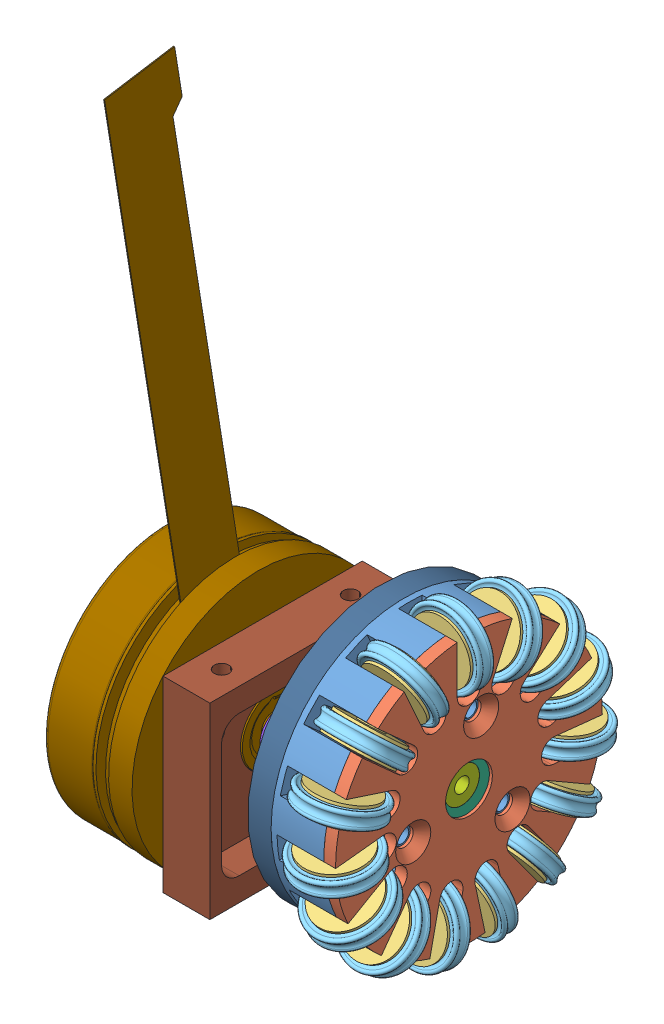
SolidWorks assembly drive_right, configuration Default. Lengths in mm.
Overall size (58.89 137.4 77.93).
70 component instances, 12 part files, 25 mates.
Components (placement in the parent):
- wheel_hub_flat_back-1: wheel_hub_flat_back [Default] at (-31.4027 -2.3485 15.5279) size (9 45.5 45.5)
- wheel_cover-1: wheel_cover [Default] at (-22.4027 -2.3485 15.5279) size (2 45.41 45.5)
- wheel_roller_asm-1: wheel_roller_asm [Default] at (-3.0698 37.2715 -2.2573) x (0.742932 0.669367 0) z (0 0 1) size (12.8 12.8 6)
  - wheel_roller_hub-1: wheel_roller_hub [Default] at (-28.6925 -1.096 17.7852) size (10.4 10.4 3.8)
  - wheel_roller_pin-1: wheel_roller_pin [Default] at (-28.6925 -1.096 14.7852) size (2.5 2.5 6)
  - xring_109-1: xring_109 [Default] at (-28.6925 -1.096 17.7852) size (12.8 12.8 2.6)
- wheel_roller_asm-2: wheel_roller_asm [Default] at (-3.0698 41.0801 15.3952) x (0.742932 0.611497 0.272256) z (0 -0.406737 0.913545) size (12.8 12.8 6)
  - wheel_roller_hub-1: wheel_roller_hub [Default] at (-28.6925 -1.096 17.7852) size (10.4 10.4 3.8)
  - wheel_roller_pin-1: wheel_roller_pin [Default] at (-28.6925 -1.096 14.7852) size (2.5 2.5 6)
  - xring_109-1: xring_109 [Default] at (-28.6925 -1.096 17.7852) size (12.8 12.8 2.6)
- wheel_roller_asm-3: wheel_roller_asm [Default] at (-3.0698 37.3795 33.0707) x (0.742932 0.447894 0.497437) z (0 -0.743145 0.669131) size (12.8 12.8 6)
  - wheel_roller_hub-1: wheel_roller_hub [Default] at (-28.6925 -1.096 17.7852) size (10.4 10.4 3.8)
  - wheel_roller_pin-1: wheel_roller_pin [Default] at (-28.6925 -1.096 14.7852) size (2.5 2.5 6)
  - xring_109-1: xring_109 [Default] at (-28.6925 -1.096 17.7852) size (12.8 12.8 2.6)
- wheel_roller_asm-4: wheel_roller_asm [Default] at (-3.0698 26.8095 47.7129) x (0.742932 0.206846 0.636606) z (0 -0.951057 0.309017) size (12.8 12.8 6)
  - wheel_roller_hub-1: wheel_roller_hub [Default] at (-28.6925 -1.096 17.7852) size (10.4 10.4 3.8)
  - wheel_roller_pin-1: wheel_roller_pin [Default] at (-28.6925 -1.096 14.7852) size (2.5 2.5 6)
  - xring_109-1: xring_109 [Default] at (-28.6925 -1.096 17.7852) size (12.8 12.8 2.6)
- wheel_roller_asm-5: wheel_roller_asm [Default] at (-3.0698 11.1979 56.79) x (0.742932 -0.069968 0.6657) z (0 -0.994522 -0.104528) size (12.8 12.8 6)
  - wheel_roller_hub-1: wheel_roller_hub [Default] at (-28.6925 -1.096 17.7852) size (10.4 10.4 3.8)
  - wheel_roller_pin-1: wheel_roller_pin [Default] at (-28.6925 -1.096 14.7852) size (2.5 2.5 6)
  - xring_109-1: xring_109 [Default] at (-28.6925 -1.096 17.7852) size (12.8 12.8 2.6)
- wheel_roller_asm-6: wheel_roller_asm [Default] at (-3.0698 -6.7561 58.7325) x (0.742932 -0.334684 0.579689) z (0 -0.866025 -0.5) size (12.8 12.8 6)
  - wheel_roller_hub-1: wheel_roller_hub [Default] at (-28.6925 -1.096 17.7852) size (10.4 10.4 3.8)
  - wheel_roller_pin-1: wheel_roller_pin [Default] at (-28.6925 -1.096 14.7852) size (2.5 2.5 6)
  - xring_109-1: xring_109 [Default] at (-28.6925 -1.096 17.7852) size (12.8 12.8 2.6)
- wheel_roller_asm-7: wheel_roller_asm [Default] at (-3.0698 -23.9479 53.2045) x (0.742932 -0.541529 0.393444) z (0 -0.587785 -0.809017) size (12.8 12.8 6)
  - wheel_roller_hub-1: wheel_roller_hub [Default] at (-28.6925 -1.096 17.7852) size (10.4 10.4 3.8)
  - wheel_roller_pin-1: wheel_roller_pin [Default] at (-28.6925 -1.096 14.7852) size (2.5 2.5 6)
  - xring_109-1: xring_109 [Default] at (-28.6925 -1.096 17.7852) size (12.8 12.8 2.6)
- wheel_roller_asm-8: wheel_roller_asm [Default] at (-3.0698 -37.405 41.162) x (0.742932 -0.65474 0.139169) z (0 -0.207912 -0.978148) size (12.8 12.8 6)
  - wheel_roller_hub-1: wheel_roller_hub [Default] at (-28.6925 -1.096 17.7852) size (10.4 10.4 3.8)
  - wheel_roller_pin-1: wheel_roller_pin [Default] at (-28.6925 -1.096 14.7852) size (2.5 2.5 6)
  - xring_109-1: xring_109 [Default] at (-28.6925 -1.096 17.7852) size (12.8 12.8 2.6)
- wheel_roller_asm-9: wheel_roller_asm [Default] at (-3.0698 -44.8005 24.687) x (0.742932 -0.65474 -0.139169) z (0 0.207912 -0.978148) size (12.8 12.8 6)
  - wheel_roller_hub-1: wheel_roller_hub [Default] at (-28.6925 -1.096 17.7852) size (10.4 10.4 3.8)
  - wheel_roller_pin-1: wheel_roller_pin [Default] at (-28.6925 -1.096 14.7852) size (2.5 2.5 6)
  - xring_109-1: xring_109 [Default] at (-28.6925 -1.096 17.7852) size (12.8 12.8 2.6)
- wheel_roller_asm-10: wheel_roller_asm [Default] at (-3.0698 -44.8557 6.6284) x (0.742932 -0.541529 -0.393444) z (0 0.587785 -0.809017) size (12.8 12.8 6)
  - wheel_roller_hub-1: wheel_roller_hub [Default] at (-28.6925 -1.096 17.7852) size (10.4 10.4 3.8)
  - wheel_roller_pin-1: wheel_roller_pin [Default] at (-28.6925 -1.096 14.7852) size (2.5 2.5 6)
  - xring_109-1: xring_109 [Default] at (-28.6925 -1.096 17.7852) size (12.8 12.8 2.6)
- wheel_roller_asm-11: wheel_roller_asm [Default] at (-3.0698 -37.561 -9.8914) x (0.742932 -0.334684 -0.579689) z (0 0.866025 -0.5) size (12.8 12.8 6)
  - wheel_roller_hub-1: wheel_roller_hub [Default] at (-28.6925 -1.096 17.7852) size (10.4 10.4 3.8)
  - wheel_roller_pin-1: wheel_roller_pin [Default] at (-28.6925 -1.096 14.7852) size (2.5 2.5 6)
  - xring_109-1: xring_109 [Default] at (-28.6925 -1.096 17.7852) size (12.8 12.8 2.6)
- wheel_roller_asm-12: wheel_roller_asm [Default] at (-3.0698 -24.1777 -22.016) x (0.742932 -0.069968 -0.6657) z (0 0.994522 -0.104528) size (12.8 12.8 6)
  - wheel_roller_hub-1: wheel_roller_hub [Default] at (-28.6925 -1.096 17.7852) size (10.4 10.4 3.8)
  - wheel_roller_pin-1: wheel_roller_pin [Default] at (-28.6925 -1.096 14.7852) size (2.5 2.5 6)
  - xring_109-1: xring_109 [Default] at (-28.6925 -1.096 17.7852) size (12.8 12.8 2.6)
- wheel_roller_asm-13: wheel_roller_asm [Default] at (-3.0698 -7.02 -27.6489) x (0.742932 0.206846 -0.636606) z (0 0.951057 0.309017) size (12.8 12.8 6)
  - wheel_roller_hub-1: wheel_roller_hub [Default] at (-28.6925 -1.096 17.7852) size (10.4 10.4 3.8)
  - wheel_roller_pin-1: wheel_roller_pin [Default] at (-28.6925 -1.096 14.7852) size (2.5 2.5 6)
  - xring_109-1: xring_109 [Default] at (-28.6925 -1.096 17.7852) size (12.8 12.8 2.6)
- wheel_roller_asm-14: wheel_roller_asm [Default] at (-3.0698 10.9455 -25.8162) x (0.742932 0.447894 -0.497437) z (0 0.743145 0.669131) size (12.8 12.8 6)
  - wheel_roller_hub-1: wheel_roller_hub [Default] at (-28.6925 -1.096 17.7852) size (10.4 10.4 3.8)
  - wheel_roller_pin-1: wheel_roller_pin [Default] at (-28.6925 -1.096 14.7852) size (2.5 2.5 6)
  - xring_109-1: xring_109 [Default] at (-28.6925 -1.096 17.7852) size (12.8 12.8 2.6)
- wheel_roller_asm-15: wheel_roller_asm [Default] at (-3.0698 26.6123 -16.8346) x (0.742932 0.611497 -0.272256) z (0 0.406737 0.913545) size (12.8 12.8 6)
  - wheel_roller_hub-1: wheel_roller_hub [Default] at (-28.6925 -1.096 17.7852) size (10.4 10.4 3.8)
  - wheel_roller_pin-1: wheel_roller_pin [Default] at (-28.6925 -1.096 14.7852) size (2.5 2.5 6)
  - xring_109-1: xring_109 [Default] at (-28.6925 -1.096 17.7852) size (12.8 12.8 2.6)
- MF126ZZ-1: MF126ZZ [Default] at (-21.6027 -2.3485 15.5279) x (-1 0 0) z (0 0.924225 0.381849) size (4 13.6 13.6)
- MF126ZZ-2: MF126ZZ [Default] at (-31.4027 -2.3485 15.5279) size (4 13.6 13.6)
- wheel_rod-1: wheel_rod [Default] at (-21.6027 -2.3485 15.5279) x (-1 0 0) z (0 0.924225 0.381849) size (23 8 8)
- spur_gear-1: spur_gear [Metric - Spur gear 0.5M 20T 20PA 3FW ---S20O8H8L4N] at (-35.4027 2.1015 27.209) x (1 0 0) z (0 0.134505 0.990913) size (8 10.9 10.9)
- EC45fl-200142-1: EC45fl-200142 [Default] at (-44.6027 2.1015 27.209) x (-1 0 0) z (0 -0.158938 0.987289) size (36.9 124.1 43.2)
- internal_gear_70-3: internal_gear_70 [DIN - Internal spur gear 0.5M 70T 20PA 4FW ---S70S45,5OD 1AF] at (-31.4027 -2.3485 15.5279) x (-1 0 0) z (0 -0.207912 -0.978148) size (4 45.5 45.5)
- motor_mount_right-1: motor_mount_right [Default] at (-36.6027 -15.7485 9.5279) x (-1 0 0) z (0 0 -1) size (8 32 34)
- motor_shaft_extension-1: motor_shaft_extension [Default] at (-55.0027 2.1015 27.209) x (-1 0 0) z (0 0.286562 -0.958062) size (18.5 4 4)
Mates (geometry in assembly coordinates):
- Width1: width anti-aligned: plane of wheel_hub_flat_back-1 through (-30.4027 12.1015 17.5279) normal (0 0 -1); plane of wheel_hub_flat_back-1 through (-30.4027 20.4015 13.5279) normal (0 0 1); plane of wheel_roller_asm-1/wheel_roller_hub-1 through (-24.5229 18.2173 17.4279) normal (0 0 1); plane of wheel_roller_asm-1/wheel_roller_hub-1 through (-24.9915 18.7374 13.6279) normal (0 0 -1)
- Distance1: distance = 0 mm aligned: plane of wheel_hub_flat_back-1 through (-22.4027 -2.3485 15.5279) normal (1 0 0); cylinder of wheel_roller_asm-1/wheel_roller_pin-1 through (-23.6527 17.2515 18.5279) axis (0 0 -1) radius 1.25
- Distance2: distance = 0 mm anti-aligned: cylinder of wheel_roller_asm-1/wheel_roller_pin-1 through (-23.6527 17.2515 18.5279) axis (0 0 -1) radius 1.25; plane of wheel_hub_flat_back-1 through (-24.9027 18.5015 18.5279) normal (0 -1 0)
- Concentric2: concentric aligned: cylinder of wheel_hub_flat_back-1 through (-22.4027 7.433 13.4488) axis (1 0 0) radius 1.25; cylinder of wheel_cover-1 through (-22.4037 7.433 13.4488) axis (1 0 0) radius 1.5
- Concentric3: concentric aligned: cylinder of wheel_cover-1 through (-22.4037 7.433 13.4488) axis (1 0 0) radius 1.5; cylinder of wheel_hub_flat_back-1 through (-22.4027 7.433 13.4488) axis (1 0 0) radius 1.25
- Coincident1: coincident anti-aligned: plane of wheel_hub_flat_back-1 through (-22.4027 -2.3485 15.5279) normal (1 0 0); plane of wheel_cover-1 through (-22.4027 -2.3485 15.5279) normal (-1 0 0)
- Concentric4: concentric aligned: cylinder of wheel_hub_flat_back-1 through (-22.4027 -2.3485 15.5279) axis (-1 0 0) radius 6.005; cylinder of MF126ZZ-2 through (-31.4027 -2.3485 15.5279) axis (-1 0 0) radius 6
- Coincident2: coincident anti-aligned: plane of wheel_hub_flat_back-1 through (-30.6027 -2.3485 15.5279) normal (-1 0 0); plane of MF126ZZ-2 through (-30.6027 4.4515 15.5279) normal (1 0 0)
- Concentric5: concentric anti-aligned: cylinder of wheel_hub_flat_back-1 through (-22.4027 -2.3485 15.5279) axis (-1 0 0) radius 6.005; cylinder of MF126ZZ-1 through (-21.6027 -2.3485 15.5279) axis (1 0 0) radius 6
- Coincident3: coincident anti-aligned: plane of wheel_hub_flat_back-1 through (-22.4027 -2.3485 15.5279) normal (1 0 0); plane of MF126ZZ-1 through (-22.4027 -4.9451 21.8126) normal (-1 0 0)
- Concentric6: concentric aligned: cylinder of MF126ZZ-1 through (-21.6027 -2.3485 15.5279) axis (1 0 0) radius 3; cylinder of wheel_rod-1 through (-21.6027 -2.3485 15.5279) axis (1 0 0) radius 2.99
- Coincident4: coincident anti-aligned: plane of MF126ZZ-2 through (-31.4027 0.6515 15.5279) normal (-1 0 0); plane of wheel_rod-1 through (-31.4027 -3.8759 19.2248) normal (1 0 0)
- Concentric13: concentric aligned: cylinder of spur_gear-1 through (-40.4028 2.1015 27.209) axis (1 0 0) radius 4; cylinder of EC45fl-200142-1 through (-42.1027 2.1015 27.209) axis (1 0 0) radius 2
- Concentric14: concentric anti-aligned: cylinder of wheel_hub_flat_back-1 through (-22.4027 -2.3485 15.5279) axis (-1 0 0) radius 22.75; cylinder of internal_gear_70-3 through (-21.4027 -2.3485 15.5279) axis (1 0 0) radius 22.75
- Concentric15: concentric aligned: cylinder of wheel_hub_flat_back-1 through (-31.4027 17.9481 11.2137) axis (-1 0 0) radius 0.8; cylinder of internal_gear_70-3 through (-31.4017 17.9481 11.2137) axis (-1 0 0) radius 1
- Coincident5: coincident anti-aligned: plane of wheel_hub_flat_back-1 through (-31.4027 -2.3485 15.5279) normal (-1 0 0); plane of internal_gear_70-3 through (-31.4027 1.186 32.1564) normal (1 0 0)
- Concentric16: concentric anti-aligned: cylinder of wheel_rod-1 through (-21.6027 -2.3485 15.5279) axis (1 0 0) radius 3; cylinder of motor_mount_right-1 through (-36.6017 -2.3485 15.5279) axis (-1 0 0) radius 3
- Coincident6: coincident anti-aligned: plane of wheel_rod-1 through (-36.6027 -3.4941 18.3006) normal (-1 0 0); plane of motor_mount_right-1 through (-36.6027 -15.7485 9.5279) normal (1 0 0)
- Concentric17: concentric anti-aligned: cylinder of EC45fl-200142-1 through (-44.6027 2.1015 27.209) axis (1 0 0) radius 6; cylinder of motor_mount_right-1 through (-36.6017 2.1015 27.209) axis (-1 0 0) radius 6.1
- Concentric18: concentric anti-aligned: cylinder of EC45fl-200142-1 through (-48.6027 6.0175 37.4883) axis (1 0 0) radius 1.25; cylinder of motor_mount_right-1 through (-36.6017 6.0175 37.4883) axis (-1 0 0) radius 1.5
- Coincident7: coincident anti-aligned: plane of EC45fl-200142-1 through (-44.6027 2.1015 27.209) normal (1 0 0); plane of motor_mount_right-1 through (-44.6027 -15.7485 9.5279) normal (-1 0 0)
- Parallel1: parallel anti-aligned: plane of motor_mount_right-1 through (-44.6027 -15.7485 9.5279) normal (0 -1 0); plane of assembly through (0 0 0) normal (0 1 0)
- Coincident8: coincident aligned: plane of spur_gear-1 through (-35.4027 2.1015 27.209) normal (-1 0 0); plane of internal_gear_70-3 through (-35.4027 1.186 32.1564) normal (-1 0 0)
- Concentric19: concentric: cylinder of EC45fl-200142-1 through (-61.0027 2.1015 27.209) axis (-1 0 0) radius 1.025; cylinder of motor_shaft_extension-1 through (-73.5027 2.1015 27.209) axis (-1 0 0) radius 1.25
- Coincident9: coincident anti-aligned: plane of EC45fl-200142-1 through (-61.0027 2.1015 27.209) normal (-1 0 0); plane of motor_shaft_extension-1 through (-61.0027 3.2991 27.5672) normal (1 0 0)
